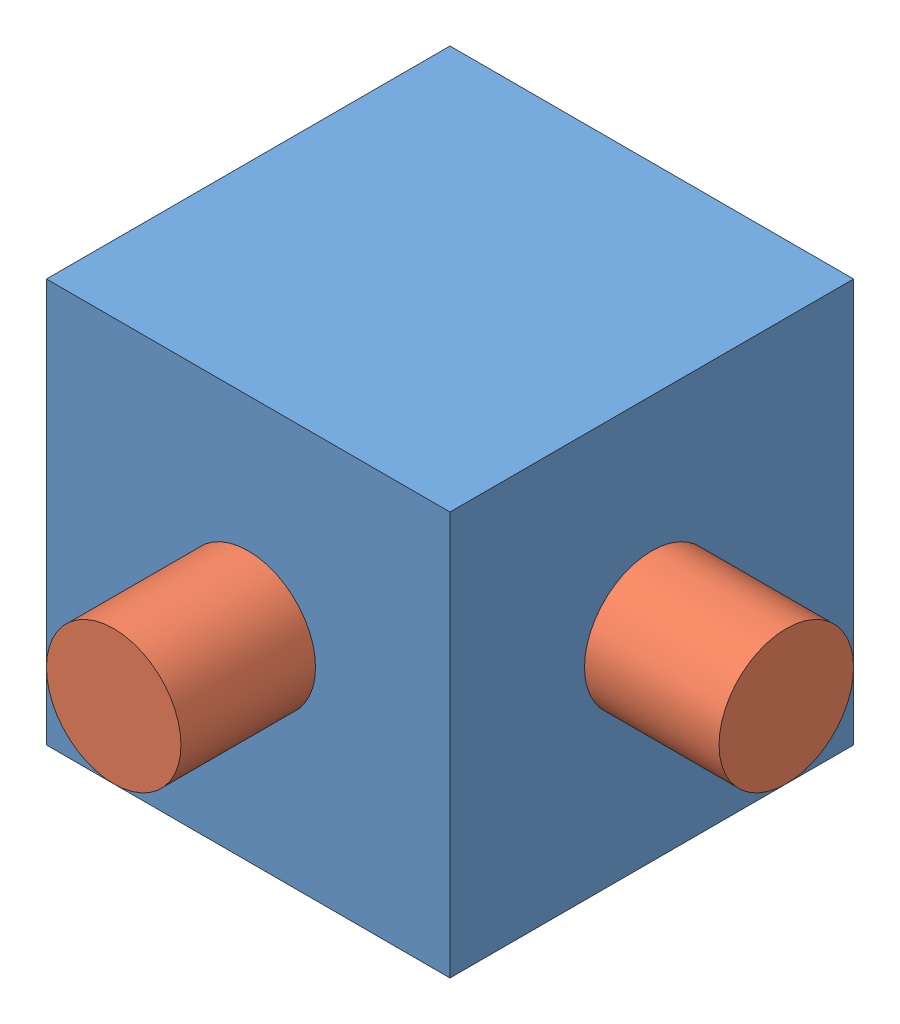
SolidWorks assembly 110303047-94, configuration 預設. Lengths in mm.
Overall size (20 12 20).
5 component instances, 2 part files, 4 mates.
Components (placement in the parent):
- Part-8-1: Part-8 [預設] at (-0.7641 -6.9869 12) size (12 12 12)
- Part-9-1: Part-9 [預設] at (6.2359 -0.9869 12) size (6 4 4)
- Part-9-2: Part-9 [預設] at (-7.7641 -0.9869 12) size (6 4 4)
- Part-9-3: Part-9 [預設] at (-0.7641 -0.9869 19) x (0 0 -1) z (1 0 0) size (6 4 4)
- Part-9-4: Part-9 [預設] at (-0.7641 -0.9869 5) x (0 0 -1) z (1 0 0) size (6 4 4)
Mates (geometry in assembly coordinates):
- 輪廓中心1: profile center: circle of Part-9-4; plane of Part-8-1 through (-0.7641 -0.9869 8) normal (0 0 -1)
- 輪廓中心2: profile center: plane of Part-8-1 through (3.2359 -0.9869 12) normal (1 0 0); circle of Part-9-1
- 輪廓中心3: profile center: plane of Part-8-1 through (-0.7641 -0.9869 16) normal (0 0 1); circle of Part-9-3
- 輪廓中心4: profile center: plane of Part-9-2 through (-4.7641 -0.9869 12) normal (1 0 0); circle of Part-8-1
